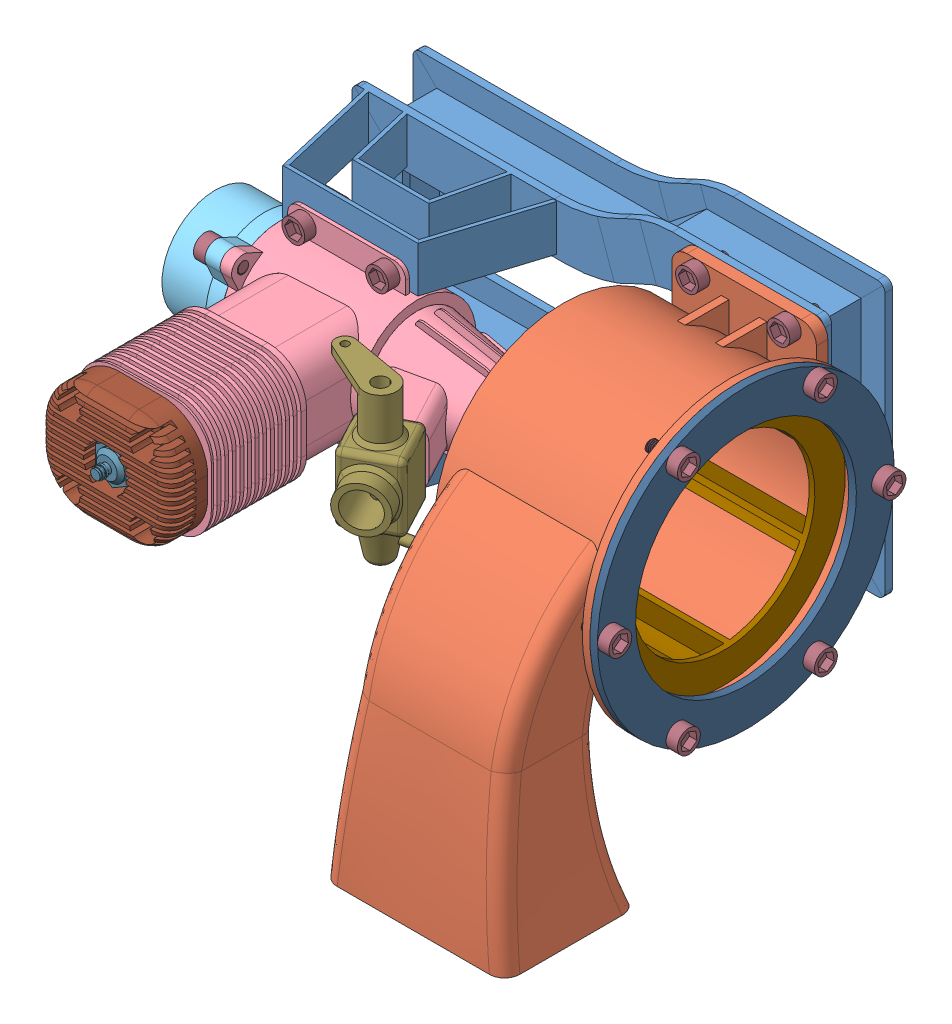
SolidWorks assembly Assem2, configuration Default. Lengths in mm.
Overall size (142.4 120.28 119.77).
32 component instances, 15 part files, 44 mates.
Components (placement in the parent):
- 1. Frame-1: 1. Frame [Default] at origin size (124 72 46)
- 2. Impellor housing-1: 2. Impellor housing [Default] at (106 0 46.5) x (0 1 0) z (1 0 0) size (106 101.06 50.69)
- Crank Shaft-1: Crank Shaft [Default] at (93.0979 0 46.5) x (0 -0.130466 0.991453) z (0 -0.991453 -0.130466) size (25.26 70.28 26.5)
- engine block-1: engine block [Default] at (69.5979 0 46.5) x (-1 0 0) z (0 1 0) size (60 69.73 44)
- Engine cover-1: Engine cover [Default] at (9.5979 0 46.5) x (-1 0 0) z (0 -0.707107 -0.707107) size (17 42 42)
- piston-1: piston [Default] at (27.5979 0 87.5764) x (-1 0 0) z (0 1 0) size (21 18.5 21)
- piston pin-1: piston pin [Default] at (27.5979 0 79.5764) x (0 -0.957523 -0.288357) z (0 -0.288357 0.957523) size (5 20 5)
- connecting rod-2: connecting rod [Default] at (27.5979 3.9658 63.56) x (0 0.240352 -0.970686) z (0 -0.970686 -0.240352) size (42 7 9)
- 3. Impeller-1: 3. Impeller [Default] at (86.0979 0 46.5) x (0 -0.991453 -0.130466) z (1 0 0) size (64 64 57)
- 4. Flange-1: 4. Flange [Default] at (130 0 46.5) x (0 -0.5 -0.866025) z (1 0 0) size (78 78 2)
- 5. Egine Head-1: 5. Egine Head [Default] at (27.5979 0 110.5) x (0 -1 0) z (-1 0 0) size (29.3 13.8 35.36)
- Carburator-1: Carburator [Default] at (67.8741 9 66.0361) x (0 -1 0) z (-0.883381 0 0.468656) size (40 28 22.14)
- Bolt-1: Bolt [Default] at (2.5979 12.7279 59.2279) x (0 0.749999 0.661439) z (0 -0.661439 0.749999) size (6 10.19 6)
- Glow Plug-1: Glow Plug [Default] at (27.5979 0 106) x (0.868285 -0.496066 0) z (-0.496066 -0.868285 0) size (10.39 14 9)
- nut-1: nut [Default] at (88.5979 0 46.5) x (0 0.727128 0.686502) z (0 0.686502 -0.727128) size (13 5.06 13)
- Bolt-2: Bolt [Default] at (2.5979 -12.7279 59.2279) x (0 -0.661439 0.749999) z (0 -0.749999 -0.661439) size (6 10.19 6)
- Bolt-3: Bolt [Default] at (2.5979 -12.7279 33.7721) x (0 -0.749999 -0.661439) z (0 0.661439 -0.749999) size (6 10.19 6)
- Bolt-4: Bolt [Default] at (2.5979 12.7279 33.7721) x (0 0.661439 -0.749999) z (0 0.749999 0.661439) size (6 10.19 6)
- Bolt-5: Bolt [Default] at (135 0 82.5) x (0 0.381849 0.924225) z (0 0.924225 -0.381849) size (6 10.19 6)
- Bolt-6: Bolt [Default] at (135 -31.1769 64.5) x (0 -0.609477 0.792804) z (0 0.792804 0.609477) size (6 10.19 6)
- Bolt-7: Bolt [Default] at (135 -31.1769 28.5) x (0 -0.991327 -0.131421) z (0 -0.131421 0.991327) size (6 10.19 6)
- Bolt-8: Bolt [Default] at (135 0 10.5) x (0 -0.381849 -0.924225) z (0 -0.924225 0.381849) size (6 10.19 6)
- Bolt-9: Bolt [Default] at (135 31.1769 28.5) x (0 0.609477 -0.792804) z (0 -0.792804 -0.609477) size (6 10.19 6)
- Bolt-10: Bolt [Default] at (135 31.1769 64.5) x (0 0.991327 0.131421) z (0 0.131421 -0.991327) size (6 10.19 6)
- Bolt-19: Bolt [Default] at (118 33 24) x (1 0 0) z (0 -1 0) size (6 10.19 6)
- Bolt-20: Bolt [Default] at (94 33 24) x (1 0 0) z (0 -1 0) size (6 10.19 6)
- Bolt-21: Bolt [Default] at (118 -33 24) x (1 0 0) z (0 -1 0) size (6 10.19 6)
- Bolt-22: Bolt [Default] at (94 -33 24) x (1 0 0) z (0 -1 0) size (6 10.19 6)
- Bolt-23: Bolt [Default] at (38.5979 18.5 50) x (1 0 0) z (0 -1 0) size (6 10.19 6)
- Bolt-24: Bolt [Default] at (38.5979 -18.5 50) x (1 0 0) z (0 -1 0) size (6 10.19 6)
- Bolt-25: Bolt [Default] at (16.5979 18.5 50) x (1 0 0) z (0 -1 0) size (6 10.19 6)
- Bolt-26: Bolt [Default] at (16.5979 -18.5 50) x (1 0 0) z (0 -1 0) size (6 10.19 6)
Mates (geometry in assembly coordinates):
- Coincident7: coincident aligned: plane of 1. Frame-1 through (0 0 0) normal (0 0 1); plane of assembly through (0 0 0) normal (0 0 1)
- Coincident8: coincident aligned: plane of 1. Frame-1 through (0 0 0) normal (0 1 0); plane of assembly through (0 0 0) normal (0 1 0)
- Coincident9: coincident aligned: plane of 1. Frame-1 through (0 0 0) normal (1 0 0); plane of assembly through (0 0 0) normal (1 0 0)
- Coincident10: coincident anti-aligned: plane of 1. Frame-1 through (75 36 18) normal (0 0 1); plane of 2. Impellor housing-1 through (125 18.5405 18) normal (0 0 -1)
- Concentric8: concentric anti-aligned: cylinder of 1. Frame-1 through (118 33 -0.001) axis (0 0 1) radius 1.5; cylinder of 2. Impellor housing-1 through (118 33 18) axis (0 0 -1) radius 1.5
- Concentric9: concentric anti-aligned: cylinder of 1. Frame-1 through (94 33 -0.001) axis (0 0 1) radius 1.5; cylinder of 2. Impellor housing-1 through (94 33 18) axis (0 0 -1) radius 1.5
- Concentric10: concentric anti-aligned: cylinder of 2. Impellor housing-1 through (131.3439 0 46.5) axis (-1 0 0) radius 8; cylinder of engine block-1 through (132.7873 0 46.5) axis (1 0 0) radius 13.5
- Coincident11: coincident anti-aligned: plane of 1. Frame-1 through (9.8182 28 46) normal (0 0 1); plane of engine block-1 through (12.0979 15.4919 46) normal (0 0 -1)
- Concentric11: concentric aligned: cylinder of 1. Frame-1 through (16.5979 18.5 -0.001) axis (0 0 1) radius 1.5; cylinder of engine block-1 through (16.5979 18.5 30.999) axis (0 0 1) radius 1.5
- Concentric12: concentric aligned: cylinder of Crank Shaft-1 through (39.0979 0 46.5) axis (1 0 0) radius 6; cylinder of engine block-1 through (132.7873 0 46.5) axis (1 0 0) radius 13.5
- Concentric13: concentric anti-aligned: cylinder of Crank Shaft-1 through (23.0979 5.7543 40.9423) axis (1 0 0) radius 2.5; cylinder of connecting rod-2 through (31.0979 5.7543 40.9423) axis (-1 0 0) radius 2.5
- Coincident12: coincident anti-aligned: plane of Crank Shaft-1 through (31.0979 16.9358 51.8202) normal (-1 0 0); plane of connecting rod-2 through (31.0979 5.7543 40.9423) normal (1 0 0)
- Concentric15: concentric aligned: cylinder of engine block-1 through (27.5979 0 30.999) axis (0 0 1) radius 10.5; cylinder of piston-1 through (27.5979 0 62.9367) axis (0 0 1) radius 10.5
- Concentric16: concentric anti-aligned: cylinder of piston-1 through (38.0979 0 73.4367) axis (-1 0 0) radius 2.5; cylinder of piston pin-1 through (17.5979 0 73.4367) axis (1 0 0) radius 2.5
- Coincident13: coincident anti-aligned: plane of piston-1 through (27.5979 0 81.4367) normal (-1 0 0); plane of piston pin-1 through (27.5979 0 73.4367) normal (1 0 0)
- Concentric17: concentric anti-aligned: cylinder of piston pin-1 through (17.5979 0 73.4367) axis (1 0 0) radius 2.5; cylinder of connecting rod-2 through (31.0979 0 73.4367) axis (-1 0 0) radius 2.5
- Coincident14: coincident aligned: plane of piston pin-1 through (27.5979 0 73.4367) normal (1 0 0); plane of connecting rod-2 through (27.5979 2.8772 57.1895) normal (1 0 0)
- Concentric18: concentric aligned: cylinder of engine block-1 through (132.7873 0 46.5) axis (1 0 0) radius 13.5; cylinder of Engine cover-1 through (9.5979 0 46.5) axis (1 0 0) radius 12
- Concentric19: concentric anti-aligned: cylinder of engine block-1 through (12.5979 12.7279 59.2279) axis (-1 0 0) radius 1.5; cylinder of Engine cover-1 through (-4.9988 12.7279 59.2279) axis (1 0 0) radius 1.5
- Coincident15: coincident anti-aligned: plane of engine block-1 through (9.5979 0 62) normal (-1 0 0); plane of Engine cover-1 through (9.5979 8.4853 38.0147) normal (1 0 0)
- Coincident16: coincident anti-aligned: plane of engine block-1 through (35.5979 -5.1834 100.5) normal (0 0 1); plane of 5. Egine Head-1 through (27.5979 0 100.5) normal (0 0 -1)
- Concentric23: concentric aligned: cylinder of 2. Impellor housing-1 through (84 0 46.5) axis (1 0 0) radius 32; cylinder of 3. Impeller-1 through (69.0979 0 46.5) axis (1 0 0) radius 8
- Concentric24: concentric anti-aligned: cylinder of 2. Impellor housing-1 through (84 0 46.5) axis (1 0 0) radius 34; cylinder of 4. Flange-1 through (132 0 46.5) axis (-1 0 0) radius 39
- Concentric25: concentric anti-aligned: cylinder of engine block-1 through (-265211.4459 0 -499950.0999) axis (0.468656 0 0.883381) radius 6; cylinder of Carburator-1 through (70.5949 0 86.1009) axis (-0.468656 0 -0.883381) radius 4.49
- Concentric28: concentric anti-aligned: cylinder of engine block-1 through (18.0529 -9.545 95.5) axis (0 0 1) radius 1.5; cylinder of 5. Egine Head-1 through (18.0529 -9.545 110.5) axis (0 0 -1) radius 1.5
- Concentric30: concentric aligned: cylinder of engine block-1 through (27.5979 0 30.999) axis (0 0 1) radius 10.5; cylinder of 5. Egine Head-1 through (27.5979 0 97) axis (0 0 1) radius 10.5
- Coincident17: coincident anti-aligned: plane of Crank Shaft-1 through (62.224 -0.3284 50.988) normal (0 0.694711 0.719289); plane of 3. Impeller-1 through (81.0979 -0.3284 50.988) normal (0 -0.694711 -0.719289)
- Coincident18: coincident anti-aligned: plane of Crank Shaft-1 through (81.0979 0 46.5) normal (1 0 0); plane of 3. Impeller-1 through (81.0979 0 46.5) normal (-1 0 0)
- Coincident19: coincident anti-aligned: plane of 2. Impellor housing-1 through (130 0 46.5) normal (1 0 0); plane of 4. Flange-1 through (130 0 46.5) normal (-1 0 0)
- Concentric31: concentric aligned: cylinder of 2. Impellor housing-1 through (130 0 82.5) axis (1 0 0) radius 1.25; cylinder of 4. Flange-1 through (132 0 82.5) axis (1 0 0) radius 1.5
- Concentric33: concentric aligned: cylinder of 5. Egine Head-1 through (27.5979 0 111.2989) axis (0 0 -1) radius 3; cylinder of Glow Plug-1 through (27.5979 0 108.5) axis (0 0 -1) radius 2.75
- Concentric34: concentric aligned: cylinder of Crank Shaft-1 through (81.0979 0 46.5) axis (1 0 0) radius 2.5; cylinder of nut-1 through (133.7392 0 46.5) axis (1 0 0) radius 6.5
- Coincident20: coincident anti-aligned: plane of 3. Impeller-1 through (88.5979 0 46.5) normal (1 0 0); plane of nut-1 through (88.5979 0 46.5) normal (-1 0 0)
- Coincident21: coincident anti-aligned: plane of engine block-1 through (65.4492 -4.255 67.3226) normal (0.468656 0 0.883381); plane of Carburator-1 through (55.5067 9 72.5973) normal (-0.468656 0 -0.883381)
- Parallel7: parallel aligned: plane of engine block-1 through (-265207.6871 -7.255 -499952.094) normal (0 -1 0); plane of Carburator-1 through (55.5067 -9 72.5973) normal (0 -1 0)
- Concentric35: concentric anti-aligned: cylinder of Engine cover-1 through (-4.9988 12.7279 59.2279) axis (1 0 0) radius 1.5; cylinder of Bolt-1 through (5.5979 12.7279 59.2279) axis (-1 0 0) radius 3
- Coincident23: coincident anti-aligned: plane of Engine cover-1 through (5.5979 10.9602 35.5398) normal (-1 0 0); plane of Bolt-1 through (5.5979 12.7279 59.2279) normal (1 0 0)
- Concentric37: concentric aligned: cylinder of Bolt-5 through (132 0 82.5) axis (1 0 0) radius 3; cylinder of 4. Flange-1 through (132 0 82.5) axis (1 0 0) radius 1.5
- Coincident24: coincident anti-aligned: plane of 4. Flange-1 through (132 0 46.5) normal (1 0 0); plane of Bolt-5 through (132 0 82.5) normal (-1 0 0)
- Coincident31: coincident anti-aligned: plane of 5. Egine Head-1 through (10.0979 -5.65 104) normal (0 0 1); plane of Glow Plug-1 through (29.4581 3.2561 104) normal (0 0 -1)
- Concentric40: concentric anti-aligned: cylinder of 2. Impellor housing-1 through (118 33 18) axis (0 0 -1) radius 1.5; cylinder of Bolt-19 through (118 33 21) axis (0 0 1) radius 3
- Coincident32: coincident anti-aligned: plane of 2. Impellor housing-1 through (125 36 21) normal (0 0 1); plane of Bolt-19 through (118 33 21) normal (0 0 -1)
- Concentric41: concentric aligned: circle of 1. Frame-1; cylinder of Bolt-23 through (38.5979 18.5 47) axis (0 0 1) radius 3
- Coincident33: coincident anti-aligned: plane of engine block-1 through (12.0979 15.4919 47) normal (0 0 1); plane of Bolt-23 through (38.5979 18.5 47) normal (0 0 -1)
